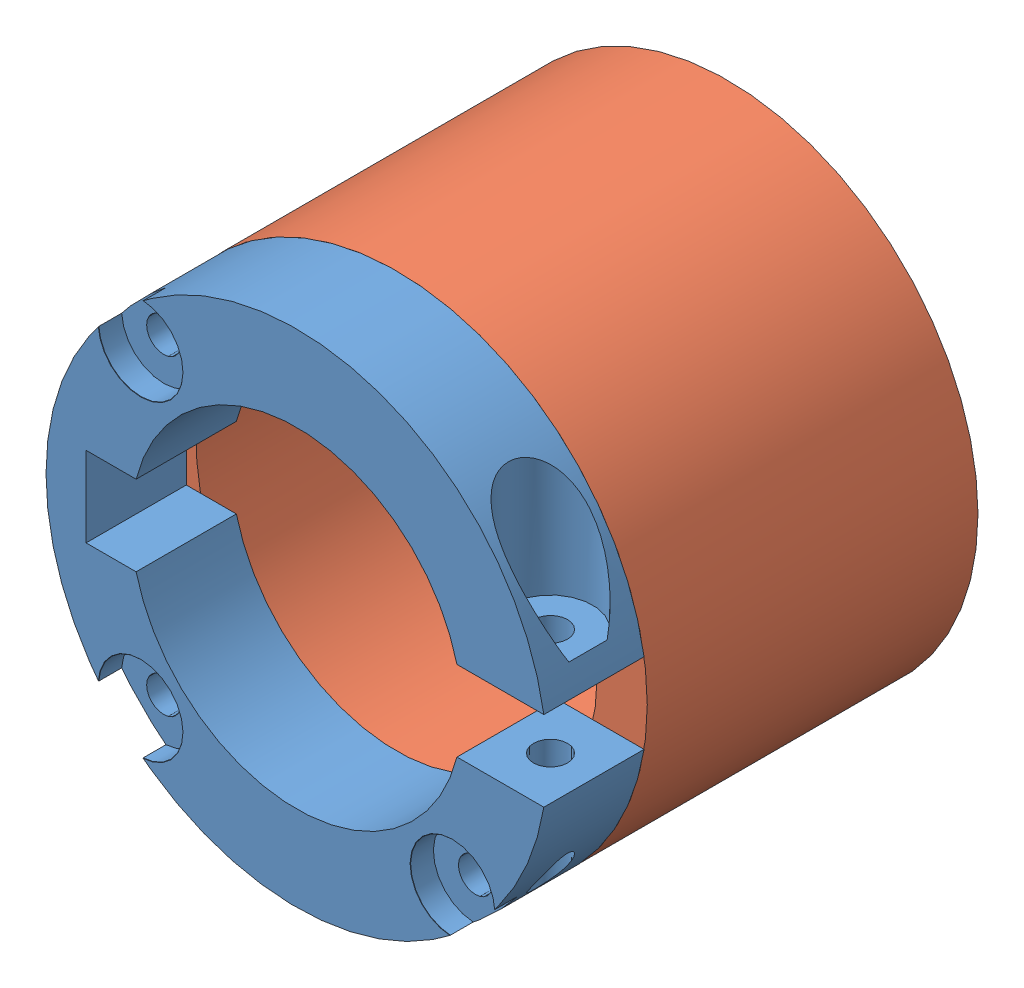
SolidWorks assembly 3WireCage, configuration Default. Lengths in mm.
Overall size (50 50 43).
2 component instances, 2 part files, 3 mates.
Components (placement in the parent):
- Motor Holder-1: Motor Holder [Default] at (11.2763 30.4367 34.4112) size (49.68 50 10)
- Fan Cage-1: Fan Cage [Default] at (11.2763 30.4367 34.4112) x (-1 0 0) z (0 0 -1) size (50 50 33)
Mates (geometry in assembly coordinates):
- Coincident1: coincident: plane of Motor Holder-1 through (11.2763 30.4367 34.4112) normal (0 0 -1); plane of Fan Cage-1 through (11.2763 30.4367 34.4112) normal (0 0 1)
- Concentric1: concentric: cylinder of Motor Holder-1 through (11.2763 30.4367 44.4112) axis (0 0 -1) radius 25; cylinder of Fan Cage-1 through (11.2763 30.4367 1.4112) axis (0 0 1) radius 25
- Parallel1: parallel: plane of Motor Holder-1 through (11.2763 26.4367 44.4112) normal (0 1 0); plane of Fan Cage-1 through (11.2763 31.4367 4.4112) normal (0 1 0)
